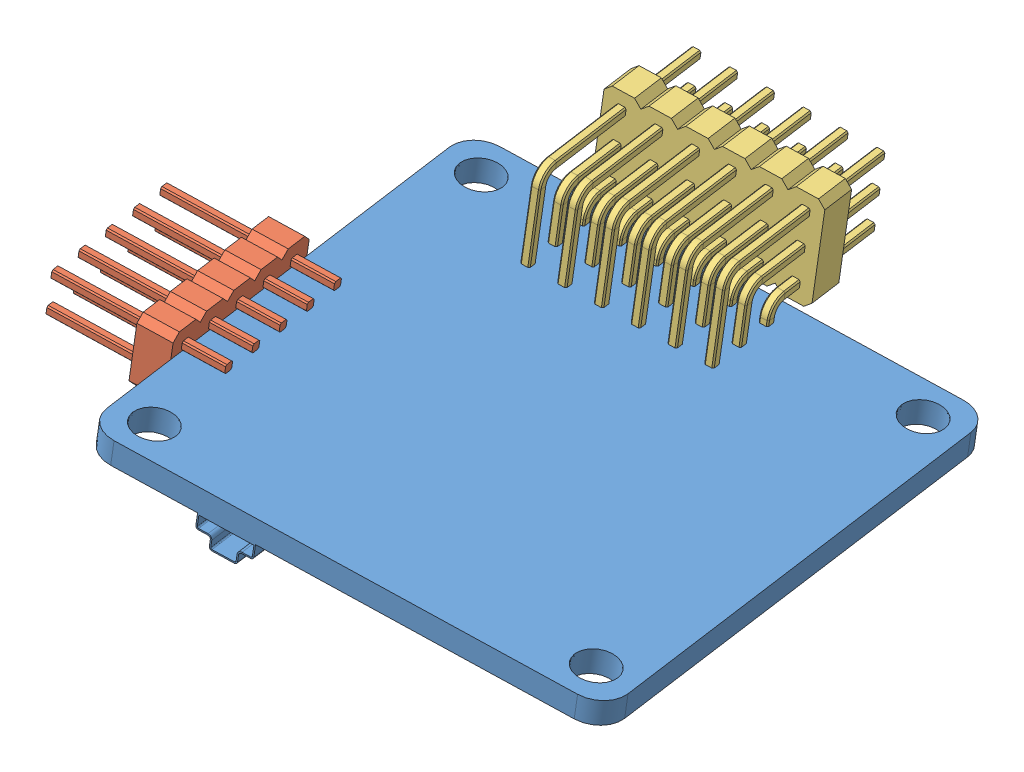
SolidWorks assembly Assem2, configuration Default. Lengths in mm.
Overall size (47.71 14.91 46.64).
3 component instances, 3 part files, 8 mates.
Components (placement in the parent):
- 11. Distribution board-1: 11. Distribution board [Default] at (24.2572 0.7836 27.5889) x (-0.981678 0.119078 0.148761) z (0.151928 0.017932 0.988229) size (36 3.75 36)
- 12. Electrical unit-1: 12. Electrical unit [Default] at (9.3602 2.9363 28.3931) x (-0.115009 -0.992723 0.035695) z (-0.151928 -0.017932 -0.988229) size (5.08 12 12.7)
- 13. Electrical unit2-1: 13. Electrical unit2 [Default] at (26.2169 -2.444 16.4176) x (-0.151928 -0.017932 -0.988229) z (0.981678 -0.119078 -0.148761) size (14.8 10.35 15.24)
Mates (geometry in assembly coordinates):
- Width1: width anti-aligned: plane of 11. Distribution board-1 through (42.3949 -0.8347 41.0204) normal (0.115009 0.992723 -0.035695); plane of 12. Electrical unit-1 through (42.1936 -2.572 41.0829) normal (-0.115009 -0.992723 0.035695); plane of 11. Distribution board-1 through (-0.8795 4.2288 40.4526) normal (-0.115009 -0.992723 0.035695); plane of 12. Electrical unit-1 through (-1.0969 2.3526 40.52) normal (0.115009 0.992723 -0.035695)
- Coincident1: coincident anti-aligned: plane of 11. Distribution board-1 through (3.9549 0.9029 14.5174) normal (-0.981678 0.119078 0.148761); plane of 12. Electrical unit-1 through (6.4152 3.2935 28.8394) normal (0.981678 -0.119078 -0.148761)
- Distance1: distance = 8 mm aligned: plane of 12. Electrical unit-1 through (5.3169 0.5103 40.6249) normal (0.151928 0.017932 0.988229); plane of 11. Distribution board-1 through (42.4975 -2.5361 43.0594) normal (0.151928 0.017932 0.988229)
- Parallel2: parallel aligned: plane of 11. Distribution board-1 through (39.2953 -3.3839 9.1621) normal (0.981678 -0.119078 -0.148761); plane of 13. Electrical unit2-1 through (27.0772 7.0038 5.9948) normal (0.981678 -0.119078 -0.148761)
- Parallel3: parallel aligned: plane of 11. Distribution board-1 through (37.0281 -3.1816 7.4831) normal (-0.151928 -0.017932 -0.988229); plane of 13. Electrical unit2-1 through (24.6976 -2.6233 6.5353) normal (-0.151928 -0.017932 -0.988229)
- Distance2: distance = 0.3 mm anti-aligned: plane of 13. Electrical unit2-1 through (25.0775 -2.5785 9.0059) normal (0.151928 0.017932 0.988229); plane of 11. Distribution board-1 through (37.0281 -3.1816 7.4831) normal (-0.151928 -0.017932 -0.988229)
- Distance3: distance = 8 mm aligned: plane of 13. Electrical unit2-1 through (12.1164 8.8185 8.2619) normal (-0.981678 0.119078 0.148761); plane of 11. Distribution board-1 through (3.9549 0.9029 14.5174) normal (-0.981678 0.119078 0.148761)
- Distance4: distance = 1.9 mm aligned: plane of 11. Distribution board-1 through (42.1936 -2.572 41.0829) normal (-0.115009 -0.992723 0.035695); plane of 13. Electrical unit2-1 through (25.7675 -0.0049 6.3233) normal (-0.115009 -0.992723 0.035695)
